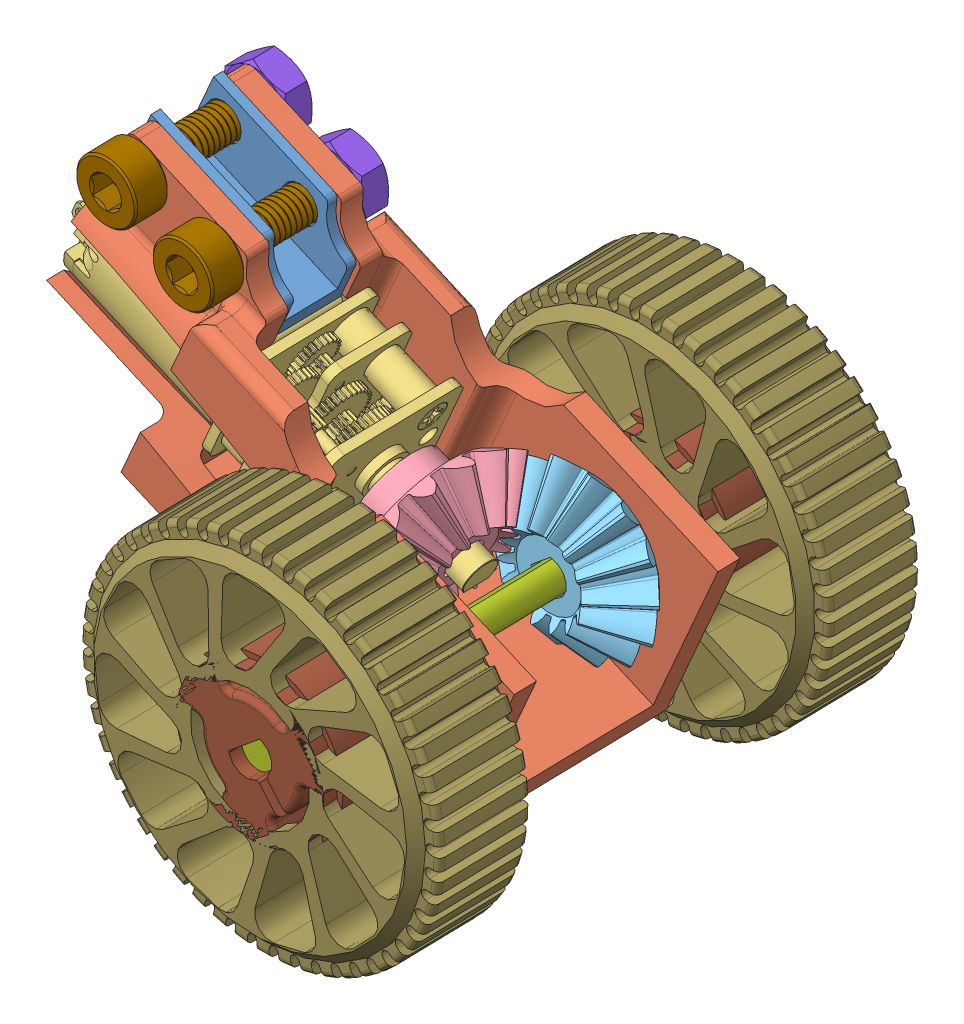
SolidWorks assembly Motor Housing 1, configuration Default. Lengths in mm.
Overall size (59.74 50 46.27).
19 component instances, 12 part files, 35 mates.
Components (placement in the parent):
- Motor Base2-2: Motor Base2 [Default] at (179.1145 -15.2226 -23.0078) x (0 -0.022393 0.999749) z (-0.911742 0.410659 0.009198) size (6.5 8.02 14.6)
- Motor Mount-1: Motor Mount [Default] at (147.1676 -83.2506 -24.5316) x (0 -0.022393 0.999749) z (-0.911742 0.410659 0.009198) size (20.4 21.28 44.97)
- micro-metal-gearmotor-1: micro-metal-gearmotor [Default] at (182.7295 -25.917 -23.2474) x (0 -0.022393 0.999749) z (0.911742 -0.410659 -0.009198) size (12 10.04 35.8)
- With_convex-Metric - Straight miter gear 1M14T 20PA 5FW-1: With_convex-Metric - Straight miter gear 1M14T 20PA 5FW [Metric - Straight miter gear 1M14T 20PA 5FW ---14O10H8MD2N] at (194.874 -31.387 -23.3699) x (0.911742 -0.410659 -0.009198) z (0.410762 0.911514 0.020416) size (7.68 15.28 15.61)
- Metric - Straight miter gear 1M14T 20PA 5FW ---14O10H8MD2N-1: Metric - Straight miter gear 1M14T 20PA 5FW ---14O10H8MD2N [Metric - Straight miter gear 1M14T 20PA 5FW ---14O10H8MD2N] at (202.2144 -34.5129 -31.4929) x (0 -0.022393 0.999749) z (0.636021 -0.771478 -0.01728) size (5.08 15.28 15.61)
- 57155K427_Stainless Steel Ball Bearing-1: 57155K427_Stainless Steel Ball Bearing [57155K427] at (202.2144 -34.9171 -13.4465) x (-0.915827 -0.401473 -0.008992) z (0 0.022393 -0.999749) size (8.1 8.1 2)
- 57155K427_Stainless Steel Ball Bearing-2: 57155K427_Stainless Steel Ball Bearing [57155K427] at (202.2144 -34.5028 -31.9418) x (1 0.00067 0.000015) z (0 -0.022393 0.999749) size (8.1 8.1 2)
- Dshaftd3l40-1: Dshaftd3l40 [Default] at (202.2144 -34.6889 -23.634) x (0 0.022393 -0.999749) z (0.771672 0.635862 0.014242) size (45 2.4 2.9)
- 90592A085_STEEL HEX NUT-1: 90592A085_STEEL HEX NUT [90592A085] at (181.7567 -14.6235 -29.446) x (0.994973 0.100115 0.002242) z (0.100141 -0.994724 -0.02228) size (5.5 2.79 6.35)
- 91290A115_Black-Oxide Alloy Steel Socket Head Screw-1: 91290A115_Black-Oxide Alloy Steel Socket Head Screw [91290A115] at (181.7567 -14.6615 -27.7465) x (0.925422 0.378842 0.008485) z (0 0.022393 -0.999749) size (5.5 5.5 13.21)
- 90592A085_STEEL HEX NUT-2: 90592A085_STEEL HEX NUT [90592A085] at (174.9187 -11.5435 -29.3771) x (0.994973 0.100115 0.002242) z (0.100141 -0.994724 -0.02228) size (5.5 2.79 6.35)
- 91290A115_Black-Oxide Alloy Steel Socket Head Screw-2: 91290A115_Black-Oxide Alloy Steel Socket Head Screw [91290A115] at (174.9187 -11.5816 -27.6775) x (0.99706 0.076603 0.001716) z (0 0.022393 -0.999749) size (5.5 5.5 13.21)
- Bevel Gear Spacer-1: Bevel Gear Spacer [Default] at (202.2144 -34.5129 -31.493) x (0.982088 -0.188374 -0.004219) z (0.188421 0.981842 0.021992) size (10 1.7 10)
- Compression Wheel v6-1: Compression Wheel v6 [Default] at (202.2144 -35.0738 -6.4482) x (-0.771672 -0.635862 -0.014242) z (0.636021 -0.771478 -0.01728) size (32.5 12.03 32.5)
  - Outer Wheel v3-1: Outer Wheel v3 [Default] at origin size (14.3 12.03 14.3)
  - COmpression Wheel v5-1: COmpression Wheel v5 [Default] at origin size (32.5 10 32.5)
- Compression Wheel v6-2: Compression Wheel v6 [Default] at (202.2144 -34.3304 -39.6399) x (0.771672 0.635862 0.014242) z (0.636021 -0.771478 -0.01728) size (32.5 12.03 32.5)
  - Outer Wheel v3-1: Outer Wheel v3 [Default] at origin size (14.3 12.03 14.3)
  - COmpression Wheel v5-1: COmpression Wheel v5 [Default] at origin size (32.5 10 32.5)
Mates (geometry in assembly coordinates):
- Coincident56: coincident aligned: plane of micro-metal-gearmotor-1 through (182.7295 -25.917 -23.2474) normal (0 -0.022393 0.999749); plane of Motor Mount-1 through (147.1676 -83.2506 -24.5316) normal (0 -0.022393 0.999749)
- Concentric35: concentric anti-aligned: cylinder of micro-metal-gearmotor-1 through (195.0608 -31.4711 -23.3718) axis (0.911742 -0.410659 -0.009198) radius 1.5; cylinder of With_convex-Metric - Straight miter gear 1M14T 20PA 5FW-1 through (199.5076 -33.474 -23.4166) axis (-0.911742 0.410659 0.009198) radius 1.7
- Parallel9: parallel anti-aligned: plane of micro-metal-gearmotor-1 through (199.6418 -34.606 -24.5603) normal (-0.410762 -0.911514 -0.020416); plane of With_convex-Metric - Straight miter gear 1M14T 20PA 5FW-1 through (199.0147 -34.5678 -23.4411) normal (0.410762 0.911514 0.020416)
- Distance1: distance = 1 mm anti-aligned: plane of micro-metal-gearmotor-1 through (191.5916 -29.9086 -23.3368) normal (0.911742 -0.410659 -0.009198); plane of With_convex-Metric - Straight miter gear 1M14T 20PA 5FW-1 through (192.5034 -30.3192 -23.346) normal (-0.911742 0.410659 0.009198)
- Coincident68: coincident: point of With_convex-Metric - Straight miter gear 1M14T 20PA 5FW-1; point of Metric - Straight miter gear 1M14T 20PA 5FW ---14O10H8MD2N-1
- Perpendicular1: perpendicular: line of With_convex-Metric - Straight miter gear 1M14T 20PA 5FW-1 through (185.7566 -27.2804 -23.2779) axis (0.911742 -0.410659 -0.009198); line of Metric - Straight miter gear 1M14T 20PA 5FW ---14O10H8MD2N-1 through (202.2144 -34.289 -41.4904) axis (0 -0.022393 0.999749)
- GearMate1: gear = 3.4 : 3.2 mm: cylinder of Metric - Straight miter gear 1M14T 20PA 5FW ---14O10H8MD2N-1 through (202.2144 -34.6267 -26.412) axis (0 0.022393 -0.999749) radius 1.6; cylinder of With_convex-Metric - Straight miter gear 1M14T 20PA 5FW-1 through (199.5076 -33.474 -23.4166) axis (-0.911742 0.410659 0.009198) radius 1.7
- Parallel12: parallel anti-aligned: plane of Motor Mount-1 through (167.6296 -10.1991 -29.3469) normal (0 -0.022393 0.999749); plane of Metric - Straight miter gear 1M14T 20PA 5FW ---14O10H8MD2N-1 through (202.2144 -34.5129 -31.493) normal (0 0.022393 -0.999749)
- Parallel14: parallel anti-aligned: plane of Metric - Straight miter gear 1M14T 20PA 5FW ---14O10H8MD2N-1 through (201.5148 -33.7781 -26.393) normal (0.636021 -0.771478 -0.01728); plane of Dshaftd3l40-1 through (201.6102 -34.4598 -1.1232) normal (-0.636021 0.771478 0.01728)
- Coincident69: coincident anti-aligned: plane of Motor Mount-1 through (206.8154 -110.345 -14.9359) normal (0 -0.022393 0.999749); plane of 57155K427_Stainless Steel Ball Bearing-1 through (200.588 -31.2134 -13.1635) normal (0 0.022393 -0.999749)
- Concentric36: concentric aligned: cylinder of Motor Mount-1 through (202.2144 -34.9216 -13.2465) axis (0 0.022393 -0.999749) radius 3.6; cylinder of 57155K427_Stainless Steel Ball Bearing-1 through (202.2144 -34.9171 -13.4465) axis (0 0.022393 -0.999749) radius 1.5
- Coincident70: coincident anti-aligned: plane of Motor Mount-1 through (183.2804 -17.198 -31.7543) normal (0 0.022393 -0.999749); plane of 57155K427_Stainless Steel Ball Bearing-2 through (202.2117 -30.4494 -32.0511) normal (0 -0.022393 0.999749)
- Concentric37: concentric anti-aligned: cylinder of Motor Mount-1 through (202.2144 -34.9216 -13.2465) axis (0 0.022393 -0.999749) radius 3.6; cylinder of 57155K427_Stainless Steel Ball Bearing-2 through (202.2144 -34.5028 -31.9418) axis (0 -0.022393 0.999749) radius 1.5
- Concentric38: concentric anti-aligned: cylinder of 57155K427_Stainless Steel Ball Bearing-2 through (202.2144 -34.5028 -31.9418) axis (0 -0.022393 0.999749) radius 1.5; cylinder of Dshaftd3l40-1 through (202.2144 -35.1927 -1.1397) axis (0 0.022393 -0.999749) radius 1.45
- Concentric94: concentric aligned: cylinder of Motor Mount-1 through (174.9187 -11.8559 -15.4316) axis (0 0.022393 -0.999749) radius 1.51; cylinder of Motor Base2-2 through (174.9187 -11.7607 -19.6795) axis (0 0.022393 -0.999749) radius 1.625
- Concentric95: concentric aligned: cylinder of Motor Mount-1 through (181.7567 -14.9358 -15.5005) axis (0 0.022393 -0.999749) radius 1.51; cylinder of Motor Base2-2 through (181.7567 -14.8407 -19.7485) axis (0 0.022393 -0.999749) radius 1.625
- Coincident152: coincident aligned: plane of Motor Mount-1 through (147.1676 -83.2506 -24.5316) normal (0 -0.022393 0.999749); plane of Motor Base2-2 through (179.1145 -15.2226 -23.0078) normal (0 -0.022393 0.999749)
- Concentric103: concentric aligned: cone of 90592A085_STEEL HEX NUT-1 through (181.7567 -14.6503 -28.2463) axis (0 0.022393 -0.999749); cone of 91290A115_Black-Oxide Alloy Steel Socket Head Screw-1 through (181.7567 -14.6615 -27.7465) axis (0 0.022393 -0.999749)
- Coincident157: coincident anti-aligned: plane of Motor Mount-1 through (149.7252 -5.0623 -28.0316) normal (0 0.022393 -0.999749); plane of 90592A085_STEEL HEX NUT-1 through (178.8616 -13.3463 -28.2171) normal (0 -0.022393 0.999749)
- Parallel30: parallel aligned: plane of Motor Base2-2 through (174.108 -8.6433 -19.6097) normal (0.410762 0.911514 0.020416); plane of 90592A085_STEEL HEX NUT-1 through (184.3339 -12.7957 -28.2048) normal (0.410762 0.911514 0.020416)
- Concentric102: concentric aligned: cone of 91290A115_Black-Oxide Alloy Steel Socket Head Screw-1 through (181.7567 -14.6615 -27.7465) axis (0 0.022393 -0.999749); cylinder of Motor Base2-2 through (181.7567 -14.8407 -19.7485) axis (0 0.022393 -0.999749) radius 1.625
- Coincident156: coincident anti-aligned: plane of Motor Mount-1 through (149.7252 -5.2975 -17.5342) normal (0 -0.022393 0.999749); plane of 91290A115_Black-Oxide Alloy Steel Socket Head Screw-1 through (181.7567 -14.8855 -17.749) normal (0 0.022393 -0.999749)
- Concentric105: concentric aligned: cone of 90592A085_STEEL HEX NUT-2 through (174.9187 -11.5704 -28.1774) axis (0 0.022393 -0.999749); cone of 91290A115_Black-Oxide Alloy Steel Socket Head Screw-2 through (174.9187 -11.5816 -27.6775) axis (0 0.022393 -0.999749)
- Coincident160: coincident anti-aligned: plane of Motor Mount-1 through (149.7252 -5.0623 -28.0316) normal (0 0.022393 -0.999749); plane of 90592A085_STEEL HEX NUT-2 through (172.0235 -10.2664 -28.1482) normal (0 -0.022393 0.999749)
- Parallel31: parallel aligned: plane of Motor Base2-2 through (174.108 -8.6433 -19.6097) normal (0.410762 0.911514 0.020416); plane of 90592A085_STEEL HEX NUT-2 through (177.4959 -9.7157 -28.1358) normal (0.410762 0.911514 0.020416)
- Coincident159: coincident anti-aligned: plane of Motor Mount-1 through (149.7252 -5.2975 -17.5342) normal (0 -0.022393 0.999749); plane of 91290A115_Black-Oxide Alloy Steel Socket Head Screw-2 through (174.9187 -11.8055 -17.68) normal (0 0.022393 -0.999749)
- Concentric104: concentric aligned: cylinder of Motor Base2-2 through (174.9187 -11.7607 -19.6795) axis (0 0.022393 -0.999749) radius 1.625; cone of 91290A115_Black-Oxide Alloy Steel Socket Head Screw-2 through (174.9187 -11.5816 -27.6775) axis (0 0.022393 -0.999749)
- Coincident254: coincident anti-aligned: plane of Metric - Straight miter gear 1M14T 20PA 5FW ---14O10H8MD2N-1 through (202.2144 -34.5129 -31.493) normal (0 0.022393 -0.999749); plane of Bevel Gear Spacer-1 through (202.2144 -34.5129 -31.493) normal (0 -0.022393 0.999749)
- Concentric157: concentric anti-aligned: cylinder of Dshaftd3l40-1 through (202.2144 -35.1927 -1.1397) axis (0 0.022393 -0.999749) radius 1.45; cylinder of Bevel Gear Spacer-1 through (202.2144 -34.4748 -33.1925) axis (0 -0.022393 0.999749) radius 1.6
- Concentric158: concentric aligned: cylinder of Dshaftd3l40-1 through (202.2144 -35.1927 -1.1397) axis (0 0.022393 -0.999749) radius 1.45; cylinder of Compression Wheel v6-1/Outer Wheel v3-1 through (202.2144 -34.9031 -14.0692) axis (0 0.022393 -0.999749) radius 3.5
- Parallel32: parallel anti-aligned: plane of Dshaftd3l40-1 through (201.6102 -34.4598 -1.1232) normal (-0.636021 0.771478 0.01728); plane of Compression Wheel v6-1/Outer Wheel v3-1 through (203.1389 -33.384 -0.4089) normal (0.636021 -0.771478 -0.01728)
- Coincident258: coincident anti-aligned: plane of 57155K427_Stainless Steel Ball Bearing-1 through (201.0498 -32.2843 -12.3872) normal (0 -0.022393 0.999749); plane of Compression Wheel v6-1/Outer Wheel v3-1 through (199.9883 -32.2393 -12.3862) normal (0 0.022393 -0.999749)
- Concentric159: concentric anti-aligned: cylinder of Dshaftd3l40-1 through (202.2144 -35.1927 -1.1397) axis (0 0.022393 -0.999749) radius 1.45; cylinder of Compression Wheel v6-2/Outer Wheel v3-1 through (202.2144 -34.5011 -32.0189) axis (0 -0.022393 0.999749) radius 3.5
- Parallel33: parallel anti-aligned: plane of Dshaftd3l40-1 through (201.6102 -34.4598 -1.1232) normal (-0.636021 0.771478 0.01728); plane of Compression Wheel v6-2/Outer Wheel v3-1 through (200.2468 -34.755 -45.6509) normal (0.636021 -0.771478 -0.01728)
- Coincident260: coincident anti-aligned: plane of Motor Mount-1 through (206.8154 -109.8882 -35.3308) normal (0 0.022393 -0.999749); plane of Compression Wheel v6-2/Outer Wheel v3-1 through (199.9883 -31.7646 -33.5809) normal (0 -0.022393 0.999749)
